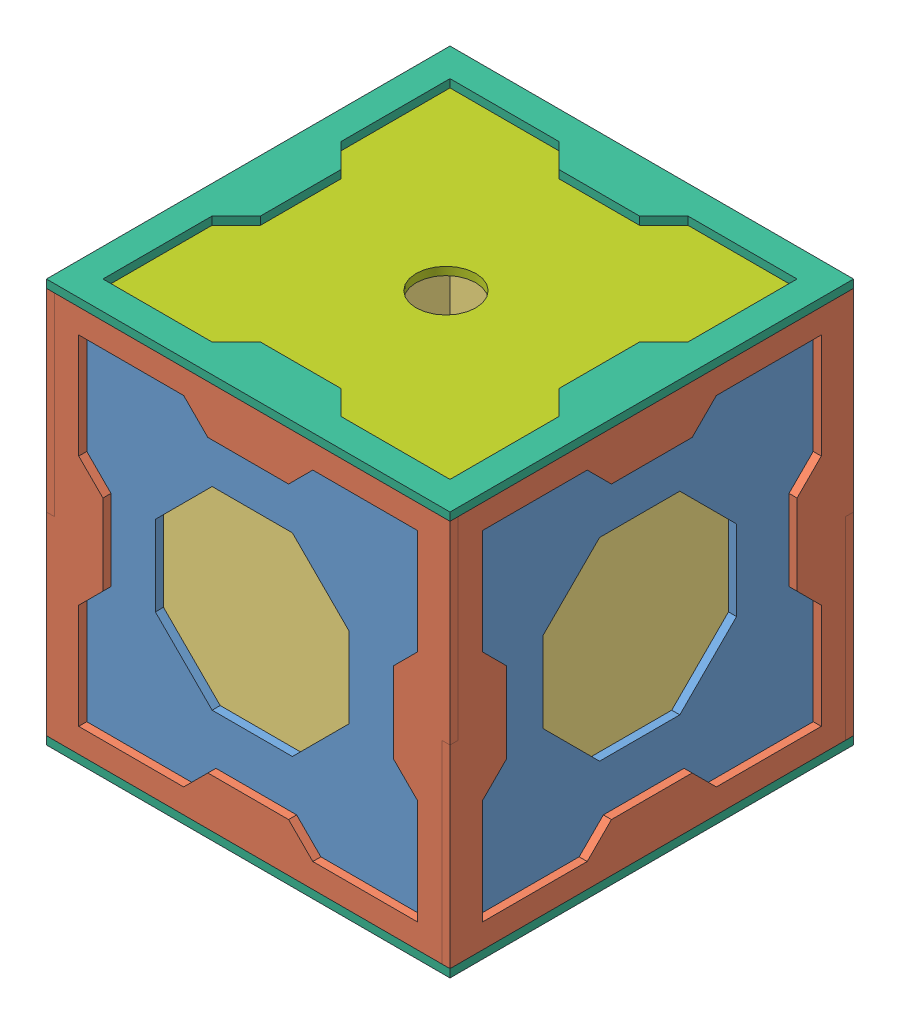
SolidWorks assembly box, configuration Default. Lengths in mm.
Overall size (158.75 158.75 158.75).
17 component instances, 7 part files, 48 mates.
Components (placement in the parent):
- wall-1: wall [Default] at (47.2467 76.5732 121.6511) size (152.4 152.4 3.18)
- wall-3: wall [Default] at (121.8592 76.5732 50.2136) x (0 0 -1) z (1 0 0) size (152.4 152.4 3.18)
- wall-4: wall [Default] at (-24.1908 76.5732 47.0386) x (0 0 1) z (-1 0 0) size (152.4 152.4 3.18)
- ext design-1: ext design [Default] at (-27.3658 76.5732 48.6261) x (0 0 1) z (-1 0 0) size (158.75 152.4 3.18)
- ext design-2: ext design [Default] at (48.8342 76.5732 124.8261) size (158.75 152.4 3.18)
- ext design-3: ext design [Default] at (125.0342 76.5732 48.6261) x (0 0 -1) z (1 0 0) size (158.75 152.4 3.18)
- ext design-4: ext design [Default] at (48.8342 76.5732 -27.5739) x (-1 0 0) z (0 0 -1) size (158.75 152.4 3.18)
- int wall-1: int wall [Default] at (121.8592 76.5732 47.0386) x (0 0 1) z (-1 0 0) size (142.88 146.05 3.17)
- int wall-2: int wall [Default] at (47.2467 76.5732 -24.3989) size (142.88 146.05 3.17)
- int wall-3: int wall [Default] at (-21.0158 76.5732 50.2136) x (0 0 1) z (-1 0 0) size (142.88 146.05 3.17)
- int wall-4: int wall [Default] at (50.4217 76.5732 118.4761) size (142.88 146.05 3.17)
- wall-5: wall [Default] at (50.4217 76.5732 -24.3989) x (-1 0 0) z (0 0 -1) size (152.4 152.4 3.18)
- bottom-1: bottom [Default] at (47.2467 3.5482 121.6511) x (-1 0 0) z (0 -1 0) size (152.4 152.4 3.17)
- bottom int-1: bottom int [Default] at (47.2467 3.5482 121.6511) x (1 0 0) z (0 1 0) size (139.7 139.7 3.17)
- bottom ext-1: bottom ext [Default] at (48.8342 -2.8018 48.6261) x (1 0 0) z (0 1 0) size (158.75 158.75 3.17)
- top wall-1: top wall [Default] at (-21.0158 149.5982 50.2136) x (0 0 1) z (0 1 0) size (146.05 146.05 3.17)
- bottom ext-2: bottom ext [Default] at (48.8342 155.9482 48.6261) x (1 0 0) z (0 -1 0) size (158.75 158.75 3.17)
Mates (geometry in assembly coordinates):
- Coincident1: coincident anti-aligned: plane of wall-1 through (47.2467 76.5732 124.8261) normal (0 0 1); plane of ext design-2 through (48.8342 76.5732 124.8261) normal (0 0 -1)
- Coincident2: coincident aligned: plane of wall-1 through (47.2467 152.7732 124.8261) normal (0 1 0); plane of ext design-2 through (48.8342 152.7732 128.0011) normal (0 1 0)
- Coincident4: coincident anti-aligned: plane of wall-3 through (125.0342 76.5732 50.2136) normal (1 0 0); plane of ext design-3 through (125.0342 76.5732 48.6261) normal (-1 0 0)
- Coincident6: coincident anti-aligned: plane of wall-4 through (-27.3658 76.5732 47.0386) normal (-1 0 0); plane of ext design-1 through (-27.3658 76.5732 48.6261) normal (1 0 0)
- Coincident8: coincident aligned: plane of wall-3 through (125.0342 152.7732 50.2136) normal (0 1 0); plane of ext design-3 through (128.2092 152.7732 48.6261) normal (0 1 0)
- Coincident16: coincident aligned: plane of wall-4 through (-27.3658 152.7732 47.0386) normal (0 1 0); plane of ext design-1 through (-30.5408 152.7732 48.6261) normal (0 1 0)
- Coincident18: coincident anti-aligned: plane of wall-1 through (-24.1908 76.5732 124.8261) normal (-1 0 0); plane of wall-4 through (-24.1908 76.5732 47.0386) normal (1 0 0)
- Coincident19: coincident anti-aligned: plane of wall-1 through (47.2467 76.5732 121.6511) normal (0 0 -1); plane of wall-4 through (-27.3658 76.5732 121.6511) normal (0 0 1)
- Coincident20: coincident aligned: plane of wall-1 through (47.2467 152.7732 124.8261) normal (0 1 0); plane of wall-4 through (-27.3658 152.7732 47.0386) normal (0 1 0)
- Coincident22: coincident aligned: plane of wall-3 through (125.0342 152.7732 50.2136) normal (0 1 0); plane of wall-1 through (47.2467 152.7732 124.8261) normal (0 1 0)
- Coincident26: coincident anti-aligned: plane of wall-1 through (121.8592 76.5732 124.8261) normal (1 0 0); plane of wall-3 through (121.8592 76.5732 50.2136) normal (-1 0 0)
- Coincident27: coincident anti-aligned: plane of wall-1 through (47.2467 76.5732 121.6511) normal (0 0 -1); plane of int wall-4 through (50.4217 76.5732 121.6511) normal (0 0 1)
- Coincident28: coincident anti-aligned: plane of wall-3 through (121.8592 76.5732 50.2136) normal (-1 0 0); plane of int wall-4 through (121.8592 3.5482 121.6511) normal (1 0 0)
- Coincident29: coincident aligned: plane of wall-1 through (47.2467 3.5482 124.8261) normal (0 -1 0); plane of int wall-4 through (121.8592 3.5482 121.6511) normal (0 -1 0)
- Coincident30: coincident anti-aligned: plane of wall-3 through (121.8592 76.5732 50.2136) normal (-1 0 0); plane of int wall-1 through (121.8592 76.5732 47.0386) normal (1 0 0)
- Coincident32: coincident anti-aligned: plane of wall-4 through (-24.1908 76.5732 47.0386) normal (1 0 0); plane of int wall-3 through (-24.1908 76.5732 50.2136) normal (-1 0 0)
- Coincident33: coincident aligned: plane of int wall-1 through (118.6842 3.5482 118.4761) normal (0 -1 0); plane of int wall-3 through (-24.1908 3.5482 121.6511) normal (0 -1 0)
- Coincident34: coincident aligned: plane of int wall-1 through (118.6842 3.5482 118.4761) normal (0 -1 0); plane of int wall-2 through (118.6842 3.5482 -21.2239) normal (0 -1 0)
- Coincident35: coincident aligned: plane of int wall-1 through (118.6842 3.5482 118.4761) normal (0 -1 0); plane of int wall-4 through (121.8592 3.5482 121.6511) normal (0 -1 0)
- Coincident38: coincident anti-aligned: plane of wall-1 through (47.2467 76.5732 121.6511) normal (0 0 -1); plane of int wall-3 through (-24.1908 3.5482 121.6511) normal (0 0 1)
- Coincident39: coincident anti-aligned: plane of int wall-1 through (118.6842 76.5732 47.0386) normal (-1 0 0); plane of int wall-2 through (118.6842 3.5482 -21.2239) normal (1 0 0)
- Coincident48: coincident anti-aligned: plane of int wall-2 through (47.2467 76.5732 -24.3989) normal (0 0 -1); plane of wall-5 through (50.4217 76.5732 -24.3989) normal (0 0 1)
- Coincident49: coincident aligned: plane of wall-3 through (125.0342 152.7732 50.2136) normal (0 1 0); plane of wall-5 through (50.4217 152.7732 -27.5739) normal (0 1 0)
- Coincident50: coincident anti-aligned: plane of ext design-3 through (125.0342 76.5732 48.6261) normal (-1 0 0); plane of wall-5 through (125.0342 76.5732 -27.5739) normal (1 0 0)
- InPlace2: in place: plane of wall-1 through (47.2467 3.5482 124.8261) normal (0 -1 0); plane of ? through (0 3.5482 0) normal (0 -1 0); moOrthogonalPlaneRef_w of wall-1 through (47.2467 3.5482 124.8261) normal (0 -1 0); unknown of ?; plane of wall-1 through (47.2467 3.5482 124.8261) normal (0 -1 0); line of ? through (-55 0 3.5482) axis (0 -1 0); plane of wall-1 through (47.2467 3.5482 124.8261) normal (0 -1 0); unknown of bottom-1
- Coincident51: coincident aligned: plane of wall-1; plane of bottom-1
- Coincident52: coincident aligned: moOrthogonalPlaneRef_w of wall-1 through (47.2467 3.5482 121.6511) normal (0 0 -1); plane of bottom-1
- Coincident53: coincident anti-aligned: moOrthogonalPlaneRef_w of wall-1 through (47.2467 3.5482 121.6511) normal (1 0 0); plane of bottom-1
- InPlace3: in place: plane of bottom-1 through (47.2467 3.5482 121.6511) normal (0 1 0); plane of ? through (0 3.5482 0) normal (0 1 0); plane of bottom-1 through (47.2467 3.5482 121.6511) normal (0 1 0); plane of ? through (0 3.5482 0) normal (0 0 -1); plane of bottom-1 through (47.2467 3.5482 121.6511) normal (0 1 0); line of ? through (-55 0 3.5482) axis (0 1 0); plane of bottom-1 through (47.2467 3.5482 121.6511) normal (0 1 0); unknown of bottom int-1
- Coincident54: coincident aligned: plane of bottom-1; plane of bottom int-1
- Coincident55: coincident aligned: moOrthogonalPlaneRef_w of bottom-1 through (47.2467 3.5482 121.6511) normal (0 0 -1); plane of bottom int-1 through (47.2467 3.5482 121.6511) normal (0 0 -1)
- Coincident56: coincident anti-aligned: moOrthogonalPlaneRef_w of bottom-1 through (47.2467 3.5482 121.6511) normal (-1 0 0); plane of bottom int-1
- Coincident57: coincident anti-aligned: plane of bottom-1 through (47.2467 0.3732 121.6511) normal (0 -1 0); plane of bottom ext-1 through (48.8342 0.3732 48.6261) normal (0 1 0)
- Coincident58: coincident aligned: plane of ext design-2 through (48.8342 76.5732 128.0011) normal (0 0 1); plane of bottom ext-1 through (48.8342 0.3732 128.0011) normal (0 0 1)
- Coincident59: coincident aligned: plane of ext design-1 through (-30.5408 76.5732 48.6261) normal (-1 0 0); plane of bottom ext-1 through (-30.5408 0.3732 48.6261) normal (-1 0 0)
- Coincident60: coincident aligned: plane of ext design-2 through (128.2092 0.3732 124.8261) normal (1 0 0); plane of ext design-3 through (128.2092 76.5732 48.6261) normal (1 0 0)
- Coincident63: coincident aligned: plane of ext design-1 through (-27.3658 0.3732 128.0011) normal (0 0 1); plane of ext design-2 through (48.8342 76.5732 128.0011) normal (0 0 1)
- Coincident65: coincident anti-aligned: plane of int wall-2 through (47.2467 76.5732 -21.2239) normal (0 0 1); plane of int wall-3 through (-24.1908 3.5482 -21.2239) normal (0 0 -1)
- InPlace4: in place: plane of int wall-3 through (-24.1908 149.5982 121.6511) normal (0 1 0); plane of ? through (0 149.5982 0) normal (0 1 0); plane of int wall-3 through (-24.1908 149.5982 121.6511) normal (0 1 0); plane of ? through (0 149.5982 0) normal (0 0 -1); plane of int wall-3 through (-24.1908 149.5982 121.6511) normal (0 1 0); line of ? through (-55 0 149.5982) axis (0 1 0); plane of int wall-3 through (-24.1908 149.5982 121.6511) normal (0 1 0); unknown of top wall-1
- Coincident66: coincident aligned: plane of int wall-3; plane of top wall-1
- Coincident67: coincident aligned: moOrthogonalPlaneRef_w of int wall-3 through (-21.0158 149.5982 50.2136) normal (1 0 0); plane of top wall-1
- Coincident68: coincident anti-aligned: moOrthogonalPlaneRef_w of int wall-3 through (-21.0158 149.5982 50.2136) normal (0 0 -1); plane of top wall-1
- Coincident69: coincident anti-aligned: plane of top wall-1 through (-21.0158 152.7732 50.2136) normal (0 1 0); plane of bottom ext-2 through (48.8342 152.7732 48.6261) normal (0 -1 0)
- Coincident70: coincident aligned: plane of ext design-2 through (48.8342 76.5732 128.0011) normal (0 0 1); plane of bottom ext-2 through (48.8342 152.7732 128.0011) normal (0 0 1)
- Coincident71: coincident aligned: plane of ext design-3 through (128.2092 76.5732 48.6261) normal (1 0 0); plane of bottom ext-2 through (128.2092 152.7732 48.6261) normal (1 0 0)
- Coincident72: coincident anti-aligned: plane of ext design-4 through (48.8342 76.5732 -27.5739) normal (0 0 1); plane of wall-5 through (50.4217 76.5732 -27.5739) normal (0 0 -1)
- Coincident73: coincident aligned: plane of ext design-1 through (-30.5408 76.5732 48.6261) normal (-1 0 0); plane of ext design-4 through (-30.5408 0.3732 -27.5739) normal (-1 0 0)
- Coincident74: coincident anti-aligned: plane of ext design-4 through (48.8342 0.3732 -30.7489) normal (0 -1 0); plane of bottom ext-1 through (48.8342 0.3732 48.6261) normal (0 1 0)
